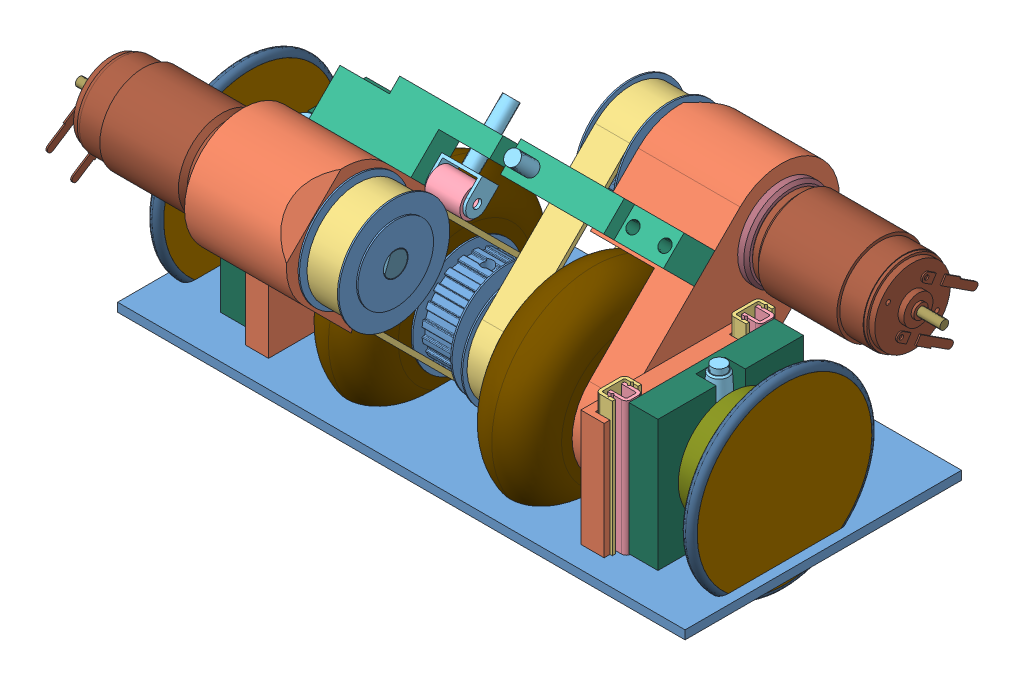
SolidWorks assembly Petit_robot_V1, configuration Défaut. Lengths in mm.
Overall size (221 114.46 134.5).
75 component instances, 28 part files, 7 mates.
Components (placement in the parent):
- Base-1: Base [Défaut] at (-162.8234 -3 31.0768) x (1 0 0) z (0 1 0) size (195 95 3)
- Assemblage1-1: Assemblage1 [Défaut] at (-11.1617 18.368 3.0291) x (0 0 -1) z (1 0 0) size (114.46 114.46 108.6)
  - Pièce3--1: Pièce3- [Défaut] at (9.4717 1.632 0) size (60 40 8)
  - glissière_L46-1: glissière_L46 [Défaut] at (-12.9661 -18.368 12.4285) x (1 0 0) z (0 1 0) size (10 8.5 46.04)
    - glissière femelle_L46--1: glissière femelle_L46- [Défaut] at (-5.5622 3.6285 0) size (10 5.8 46)
    - glissière male_L46--1: glissière male_L46- [Défaut] at (-3.4622 7.3285 -0.0384) size (5.8 6.4 46)
  - Pièce1^Assemblage1-1: Pièce1^Assemblage1 [Défaut] at origin (virtual)
  - Codeur_2MRH-1: Codeur_2MRH [Default] at (6.1831 7.1866 24.8048) size (38.09 42.8 24.5)
    - corps_codeur_2MRH-1: corps_codeur_2MRH [Default] at (3.2886 -2.5929 -14.3048) size (24 36.75 20.04)
    - mandrin_codeur_2MRH-1: mandrin_codeur_2MRH [Default] at (3.2886 -2.5929 -3.8048) x (-0.434638 0.900605 0) z (0 0 1) size (6 6 14)
    - bague_codeur_2MRH-1: bague_codeur_2MRH [Default] at (3.2886 -2.5929 5.6952) x (0.434638 -0.900605 0) z (0 0 1) size (13.5 13.48 4.5)
    - Socket Head Cap Screw_AM-2: Socket Head Cap Screw_AM [B18.3.1M - 1.6 x 0.35 x 5 Hex SHCS -- 5NHX] at (9.1066 -4.3376 7.9452) x (-0.434638 0.900605 0) z (0 0 1) (suppressed, hidden)
    - Pan Slot Head_AM-4: Pan Slot Head_AM [B18.6.7M - M2 x 0.4 x 4 Slotted PHMS --4N] at (10.6498 1.6571 7.2952) x (0 0 -1) z (0.728333 -0.685223 0) (suppressed, hidden)
    - Pan Slot Head_AM-5: Pan Slot Head_AM [B18.6.7M - M2 x 0.4 x 4 Slotted PHMS --4N] at (-4.0726 1.6571 7.2952) x (0 0 -1) z (0.998972 -0.045336 0) (suppressed, hidden)
    - Pan Slot Head_AM-6: Pan Slot Head_AM [B18.6.7M - M2 x 0.4 x 4 Slotted PHMS --4N] at (3.2886 -11.0929 7.2952) x (0 0 -1) z (-0.043781 0.999041 0) (suppressed, hidden)
    - Bride_membrane-1: Bride_membrane [Default] at (3.2886 -2.5929 5.6952) x (0.5 0.866025 0) z (-0.866025 0.5 0) size (28.11 0.5 27.75)
  - Roue_codeuse_D30--1: Roue_codeuse_D30- [Default] at (9.4717 4.5937 40) x (0.934453 0.356086 0) z (-0.356086 0.934453 0) size (60 19 60)
  - joint_D64--1: joint_D64- [Default] at (9.4717 4.5937 36) x (1 0 0) z (0 -1 0) size (64 4 64)
  - Motoreducteur_Faulhauber_3042W024_30_1-1: Motoreducteur_Faulhauber_3042W024_30_1 [Default] at (43.3376 42.3534 32.4471) x (-0.839516 0.543335 0) z (-0.543335 -0.839516 0) size (42.24 108.6 42.24)
    - corps_moteur_faulhauber_3042W024C-1: corps_moteur_faulhauber_3042W024C [Default] at (-5.2131 -12.6529 -1.1935) size (35.9 47.3 30)
    - arbre_moteur_faulhauber_3042W024C-1: arbre_moteur_faulhauber_3042W024C [Default] at (-5.2131 41.7471 -1.1935) x (0 -1 0) z (-0.776717 0 -0.629849) size (65.3 4 4)
    - corps_reducteur_faulhaber_30_1-1: corps_reducteur_faulhaber_30_1 [Default] at (-5.2131 64.4471 -1.1935) x (0.769654 0 -0.638462) z (0 -1 0) size (30 30 39.6)
    - arbre_reducteur_faulhauber_30_1-1: arbre_reducteur_faulhauber_30_1 [Default] at (-5.2131 64.4471 -1.1935) x (0.811588 0 -0.584231) z (0.584231 0 0.811588) size (8 20.6 8)
  - Pièce2-1: Pièce2 [Défaut] at (34.4717 -17.9063 21.5) x (-1 0 0) z (0 0 -1) size (50 45 10)
  - glissière_L46-2: glissière_L46 [Défaut] at (33.0339 -18.368 12.4285) x (1 0 0) z (0 1 0) size (10 8.5 46.04)
    - glissière femelle_L46--1: glissière femelle_L46- [Défaut] at (-5.5622 3.6285 0) size (10 5.8 46)
    - glissière male_L46--1: glissière male_L46- [Défaut] at (-3.4622 7.3285 -0.0384) size (5.8 6.4 46)
  - cloche-1: cloche [Défaut] at (34.4717 -17.9063 31) x (-1 0 0) z (0 0 -1) size (36 36 9.5)
  - axe roue de roller pat_2-1: axe roue de roller pat_2 [Défaut] at (9.4717 1.632 -45) x (0.66174 -0.749733 0) z (0 0 1) size (8 8 49)
  - roue_roller pleinePat-1: roue_roller pleinePat [Default] at (9.4717 1.632 -37.6) x (0.414554 0.910025 0) z (0 0 1) size (70 70 24)
  - poulie roue D38,10 L15 HPC-1: poulie roue D38,10 L15 HPC [Défaut] at (9.4717 1.632 -38.6) x (0 0 -1) z (1 0 0) size (15 38.1 38.1)
  - poulie roue D38,10 L15 HPC-2: poulie roue D38,10 L15 HPC [Défaut] at (48.3625 40.5229 -51.6) x (0 0 1) z (-0.986351 -0.164659 0) size (15 38.1 38.1)
  - bras moteur--1: bras moteur- [Défaut] at (-4.6705 -12.5101 0) x (0.707107 -0.707107 0) z (0 0 -1) size (40 95 35)
  - courroie--1: courroie- [Défaut] at (9.4717 1.632 -51.6) x (0.707107 0.707107 0) z (0 0 1) size (90 35 12)
  - galet-1: galet [Défaut] at (20.2348 44.215 -51.5) size (10 10 12)
  - axe galet-1: axe galet [Défaut] at (20.2348 44.215 -31.5) x (0.99697 0.077787 0) z (-0.077787 0.99697 0) size (10 21 10) (hidden)
  - poussoir-1: poussoir [Défaut] at (19.8813 38.9117 -52.5) x (0.707107 0.707107 0) z (0 0 1) size (8 30.5 14)
  - pont-1: pont [Défaut] at (18.4671 38.9117 0) x (0 0 -1) z (-0.707107 0.707107 0) size (52.5 10 20)
- Assemblage1-3: Assemblage1 [Défaut] at (-120.1666 18.368 -17.6137) x (0 0 1) z (-1 0 0) size (114.46 114.46 108.6)
  - Pièce3--1: Pièce3- [Défaut] at (9.4717 1.632 0) size (60 40 8)
  - glissière_L46-1: glissière_L46 [Défaut] at (-12.9661 -18.368 12.4285) x (1 0 0) z (0 1 0) size (10 8.5 46.04)
    - glissière femelle_L46--1: glissière femelle_L46- [Défaut] at (-5.5622 3.6285 0) size (10 5.8 46)
    - glissière male_L46--1: glissière male_L46- [Défaut] at (-3.4622 7.3285 -0.0384) size (5.8 6.4 46)
  - Pièce1^Assemblage1-1: Pièce1^Assemblage1 [Défaut] at origin (virtual)
  - Codeur_2MRH-1: Codeur_2MRH [Default] at (6.1831 7.1866 24.8048) size (38.09 42.8 24.5)
    - corps_codeur_2MRH-1: corps_codeur_2MRH [Default] at (3.2886 -2.5929 -14.3048) size (24 36.75 20.04)
    - mandrin_codeur_2MRH-1: mandrin_codeur_2MRH [Default] at (3.2886 -2.5929 -3.8048) x (-0.434638 0.900605 0) z (0 0 1) size (6 6 14)
    - bague_codeur_2MRH-1: bague_codeur_2MRH [Default] at (3.2886 -2.5929 5.6952) x (0.434638 -0.900605 0) z (0 0 1) size (13.5 13.48 4.5)
    - Socket Head Cap Screw_AM-2: Socket Head Cap Screw_AM [B18.3.1M - 1.6 x 0.35 x 5 Hex SHCS -- 5NHX] at (9.1066 -4.3376 7.9452) x (-0.434638 0.900605 0) z (0 0 1) (suppressed, hidden)
    - Pan Slot Head_AM-4: Pan Slot Head_AM [B18.6.7M - M2 x 0.4 x 4 Slotted PHMS --4N] at (10.6498 1.6571 7.2952) x (0 0 -1) z (0.728333 -0.685223 0) (suppressed, hidden)
    - Pan Slot Head_AM-5: Pan Slot Head_AM [B18.6.7M - M2 x 0.4 x 4 Slotted PHMS --4N] at (-4.0726 1.6571 7.2952) x (0 0 -1) z (0.998972 -0.045336 0) (suppressed, hidden)
    - Pan Slot Head_AM-6: Pan Slot Head_AM [B18.6.7M - M2 x 0.4 x 4 Slotted PHMS --4N] at (3.2886 -11.0929 7.2952) x (0 0 -1) z (-0.043781 0.999041 0) (suppressed, hidden)
    - Bride_membrane-1: Bride_membrane [Default] at (3.2886 -2.5929 5.6952) x (0.5 0.866025 0) z (-0.866025 0.5 0) size (28.11 0.5 27.75)
  - Roue_codeuse_D30--1: Roue_codeuse_D30- [Default] at (9.4717 4.5937 40) x (0.934453 0.356086 0) z (-0.356086 0.934453 0) size (60 19 60)
  - joint_D64--1: joint_D64- [Default] at (9.4717 4.5937 36) x (1 0 0) z (0 -1 0) size (64 4 64)
  - Motoreducteur_Faulhauber_3042W024_30_1-1: Motoreducteur_Faulhauber_3042W024_30_1 [Default] at (43.3376 42.3534 32.4471) x (-0.839516 0.543335 0) z (-0.543335 -0.839516 0) size (42.24 108.6 42.24)
    - corps_moteur_faulhauber_3042W024C-1: corps_moteur_faulhauber_3042W024C [Default] at (-5.2131 -12.6529 -1.1935) size (35.9 47.3 30)
    - arbre_moteur_faulhauber_3042W024C-1: arbre_moteur_faulhauber_3042W024C [Default] at (-5.2131 41.7471 -1.1935) x (0 -1 0) z (-0.776717 0 -0.629849) size (65.3 4 4)
    - corps_reducteur_faulhaber_30_1-1: corps_reducteur_faulhaber_30_1 [Default] at (-5.2131 64.4471 -1.1935) x (0.769654 0 -0.638462) z (0 -1 0) size (30 30 39.6)
    - arbre_reducteur_faulhauber_30_1-1: arbre_reducteur_faulhauber_30_1 [Default] at (-5.2131 64.4471 -1.1935) x (0.811588 0 -0.584231) z (0.584231 0 0.811588) size (8 20.6 8)
  - Pièce2-1: Pièce2 [Défaut] at (34.4717 -17.9063 21.5) x (-1 0 0) z (0 0 -1) size (50 45 10)
  - glissière_L46-2: glissière_L46 [Défaut] at (33.0339 -18.368 12.4285) x (1 0 0) z (0 1 0) size (10 8.5 46.04)
    - glissière femelle_L46--1: glissière femelle_L46- [Défaut] at (-5.5622 3.6285 0) size (10 5.8 46)
    - glissière male_L46--1: glissière male_L46- [Défaut] at (-3.4622 7.3285 -0.0384) size (5.8 6.4 46)
  - cloche-1: cloche [Défaut] at (34.4717 -17.9063 31) x (-1 0 0) z (0 0 -1) size (36 36 9.5)
  - axe roue de roller pat_2-1: axe roue de roller pat_2 [Défaut] at (9.4717 1.632 -45) x (0.66174 -0.749733 0) z (0 0 1) size (8 8 49)
  - roue_roller pleinePat-1: roue_roller pleinePat [Default] at (9.4717 1.632 -37.6) x (0.414554 0.910025 0) z (0 0 1) size (70 70 24)
  - poulie roue D38,10 L15 HPC-1: poulie roue D38,10 L15 HPC [Défaut] at (9.4717 1.632 -38.6) x (0 0 -1) z (1 0 0) size (15 38.1 38.1)
  - poulie roue D38,10 L15 HPC-2: poulie roue D38,10 L15 HPC [Défaut] at (48.3625 40.5229 -51.6) x (0 0 1) z (-0.986351 -0.164659 0) size (15 38.1 38.1)
  - bras moteur--1: bras moteur- [Défaut] at (-4.6705 -12.5101 0) x (0.707107 -0.707107 0) z (0 0 -1) size (40 95 35)
  - courroie--1: courroie- [Défaut] at (9.4717 1.632 -51.6) x (0.707107 0.707107 0) z (0 0 1) size (90 35 12)
  - galet-1: galet [Défaut] at (20.2348 44.215 -51.5) size (10 10 12)
  - axe galet-1: axe galet [Défaut] at (20.2348 44.215 -31.5) x (0.99697 0.077787 0) z (-0.077787 0.99697 0) size (10 21 10) (hidden)
  - poussoir-1: poussoir [Défaut] at (19.8813 38.9117 -52.5) x (0.707107 0.707107 0) z (0 0 1) size (8 30.5 14)
  - pont-1: pont [Défaut] at (18.4671 38.9117 0) x (0 0 -1) z (-0.707107 0.707107 0) size (52.5 10 20)
Mates (geometry in assembly coordinates):
- Coïncidente1: coincident anti-aligned: plane of Base-1 through (-162.8234 0 -63.9232) normal (0 1 0); plane of Assemblage1-1/Pièce3--1 through (-3.1617 0 -36.4425) normal (0 -1 0)
- Parallèle1: parallel anti-aligned: plane of Base-1 through (-162.8234 0 31.0768) normal (-1 0 0); plane of Assemblage1-1/Roue_codeuse_D30--1 through (28.8383 22.9616 -6.4425) normal (1 0 0)
- Coïncidente6: coincident anti-aligned: plane of Base-1 through (-162.8234 0 -63.9232) normal (0 1 0); plane of Assemblage1-3/Pièce3--1 through (-128.1666 0 21.858) normal (0 -1 0)
- Parallèle3: parallel anti-aligned: plane of Base-1 through (-162.8234 -3 -63.9232) normal (0 -1 0); plane of assembly through (0 0 0) normal (0 1 0)
- Coïncidente9: coincident aligned: plane of Base-1 through (-162.8234 0 -63.9232) normal (0 1 0); plane of assembly through (0 0 0) normal (0 1 0)
- PLAN1: unknown: plane of Base-1 through (-162.8234 0 -63.9232) normal (0 0 -1); plane of Base-1 through (-162.8234 0 31.0768) normal (0 0 1)
- PLAN2: unknown: plane of Base-1 through (-162.8234 0 31.0768) normal (-1 0 0); plane of Base-1 through (32.1766 0 31.0768) normal (1 0 0)
